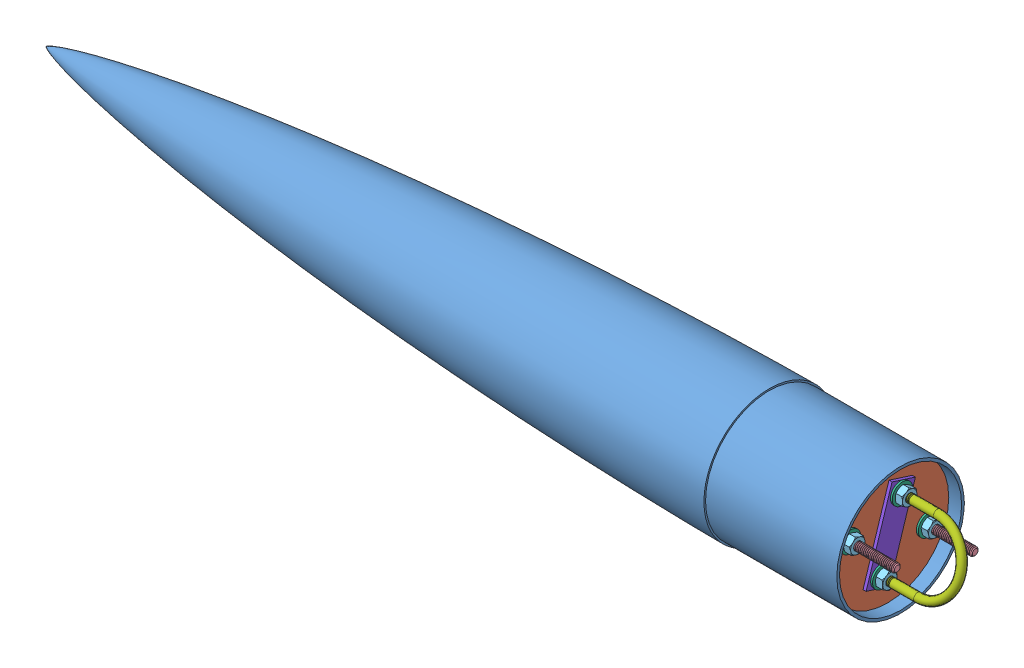
SolidWorks assembly NoseconeAssembly, configuration Default. Lengths in mm.
Overall size (713.54 119.45 119.45).
30 component instances, 8 part files, 72 mates.
Components (placement in the parent):
- NoseCone-1: NoseCone [Default] at (437.4105 322.4463 425.9996) size (664 101.6 101.6)
- CouplerBulkheadAft-1: CouplerBulkheadAft [Default] at (524.648 322.4463 425.9996) x (0 0.953259 -0.302155) z (0 -0.302155 -0.953259) size (95.15 4.76 95.15)
- CouplerBulkheadForward-1: CouplerBulkheadForward [Default] at (380.6605 322.4463 425.9996) x (0 -0.302155 -0.953259) z (0 0.953259 -0.302155) size (95.15 4.76 95.15)
- ThreadedRod_NC-1: ThreadedRod_NC [95475A576] at (465.494 312.8529 395.7337) x (1 0 0) z (0 -0.926581 -0.376095) size (206.33 6.43 7.33)
- ThreadedRod_NC-2: ThreadedRod_NC [95475A576] at (465.494 332.0398 456.2656) x (1 0 0) z (0 -0.612687 -0.790326) size (206.33 6.43 7.33)
- 91845A029_18-8 Stainless Steel Hex Nut-1: 91845A029_18-8 Stainless Steel Hex Nut [91845A029] at (371.6721 312.8529 395.7337) x (0 0.953259 -0.302155) z (-1 0 0) size (11.11 12.83 6.51)
- 91845A029_18-8 Stainless Steel Hex Nut-3: 91845A029_18-8 Stainless Steel Hex Nut [91845A029] at (371.6721 332.0398 456.2656) x (0 -0.953259 0.302155) z (-1 0 0) size (11.11 12.83 6.51)
- 91845A029_18-8 Stainless Steel Hex Nut-5: 91845A029_18-8 Stainless Steel Hex Nut [91845A029] at (384.8864 312.8529 395.7337) x (0 0.953259 -0.302155) z (-1 0 0) size (11.11 12.83 6.51)
- 91845A029_18-8 Stainless Steel Hex Nut-6: 91845A029_18-8 Stainless Steel Hex Nut [91845A029] at (384.8864 332.0398 456.2656) x (0 0.214956 -0.976624) z (1 0 0) size (11.11 12.83 6.51)
- 92141A029_18-8 Stainless Steel Washer-1: 92141A029_18-8 Stainless Steel Washer [92141A029] at (374.4502 312.8529 395.7337) x (0 -1 0) z (0 0 1) size (15.88 1.45 15.88)
- 92141A029_18-8 Stainless Steel Washer-3: 92141A029_18-8 Stainless Steel Washer [92141A029] at (380.6605 312.8529 395.7337) x (0 -1 0) z (0 0 1) size (15.88 1.45 15.88)
- 92141A029_18-8 Stainless Steel Washer-4: 92141A029_18-8 Stainless Steel Washer [92141A029] at (380.6605 332.0398 456.2656) x (0 0.711764 0.702418) z (0 0.702418 -0.711764) size (15.88 1.45 15.88)
- 92141A029_18-8 Stainless Steel Washer-5: 92141A029_18-8 Stainless Steel Washer [92141A029] at (374.4502 332.0398 456.2656) x (0 -0.99806 -0.062267) z (0 -0.062267 0.99806) size (15.88 1.45 15.88)
- 3043T618_U-Bolt-1: 3043T618_U-Bolt [3043T618] at (560.3742 322.4463 425.9996) x (0 -0.953259 0.302155) z (0 -0.302155 -0.953259) size (63.63 83.11 11.11)
- 8875T929_Mount Plate for 1 4 -20 Thread-1: 8875T929_Mount Plate for 1 4 -20 Thread [8875T929] at (529.4105 322.4463 425.9996) x (0 0.953259 -0.302155) z (1 0 0) size (66.67 19.05 2.38)
- 91845A029_18-8 Stainless Steel Hex Nut-7: 91845A029_18-8 Stainless Steel Hex Nut [91845A029] at (533.6364 332.0398 456.2656) x (0 0.214956 -0.976624) z (1 0 0) size (11.11 12.83 6.51)
- 91845A029_18-8 Stainless Steel Hex Nut-8: 91845A029_18-8 Stainless Steel Hex Nut [91845A029] at (520.4221 332.0398 456.2656) x (0 0.214956 -0.976624) z (1 0 0) size (11.11 12.83 6.51)
- 91845A029_18-8 Stainless Steel Hex Nut-9: 91845A029_18-8 Stainless Steel Hex Nut [91845A029] at (520.4221 312.8529 395.7337) x (0 0.953259 -0.302155) z (1 0 0) size (11.11 12.83 6.51)
- 91845A029_18-8 Stainless Steel Hex Nut-10: 91845A029_18-8 Stainless Steel Hex Nut [91845A029] at (533.6364 312.8529 395.7337) x (0 0.214956 -0.976624) z (1 0 0) size (11.11 12.83 6.51)
- 91845A029_18-8 Stainless Steel Hex Nut-11: 91845A029_18-8 Stainless Steel Hex Nut [91845A029] at (536.0177 298.2336 433.6744) x (0 0 1) z (1 0 0) size (11.11 12.83 6.51)
- 91845A029_18-8 Stainless Steel Hex Nut-12: 91845A029_18-8 Stainless Steel Hex Nut [91845A029] at (536.0177 346.6591 418.3249) x (0 0 1) z (1 0 0) size (11.11 12.83 6.51)
- 92141A029_18-8 Stainless Steel Washer-6: 92141A029_18-8 Stainless Steel Washer [92141A029] at (520.819 346.6591 418.3249) x (0 -0.381849 0.924225) z (0 0.924225 0.381849) size (15.88 1.45 15.88)
- 92141A029_18-8 Stainless Steel Washer-7: 92141A029_18-8 Stainless Steel Washer [92141A029] at (530.8583 332.0398 456.2656) x (0 0.996386 0.084943) z (0 -0.084943 0.996386) size (15.88 1.45 15.88)
- 92141A029_18-8 Stainless Steel Washer-8: 92141A029_18-8 Stainless Steel Washer [92141A029] at (524.648 332.0398 456.2656) x (0 0.994084 -0.108611) z (0 0.108611 0.994084) size (15.88 1.45 15.88)
- 92141A029_18-8 Stainless Steel Washer-9: 92141A029_18-8 Stainless Steel Washer [92141A029] at (530.8583 312.8529 395.7337) x (0 1 0) z (0 0 1) size (15.88 1.45 15.88)
- 92141A029_18-8 Stainless Steel Washer-10: 92141A029_18-8 Stainless Steel Washer [92141A029] at (531.7918 346.6591 418.3249) x (0 -0.381849 0.924225) z (0 0.924225 0.381849) size (15.88 1.45 15.88)
- 92141A029_18-8 Stainless Steel Washer-11: 92141A029_18-8 Stainless Steel Washer [92141A029] at (520.819 298.2336 433.6744) x (0 -0.381849 0.924225) z (0 0.924225 0.381849) size (15.88 1.45 15.88)
- 92141A029_18-8 Stainless Steel Washer-12: 92141A029_18-8 Stainless Steel Washer [92141A029] at (531.7918 298.2336 433.6744) x (0 -0.381849 0.924225) z (0 0.924225 0.381849) size (15.88 1.45 15.88)
- 92141A029_18-8 Stainless Steel Washer-13: 92141A029_18-8 Stainless Steel Washer [92141A029] at (524.648 312.8529 395.7337) x (0 1 0) z (0 0 1) size (15.88 1.45 15.88)
- 8875T929_Mount Plate for 1 4 -20 Thread-2: 8875T929_Mount Plate for 1 4 -20 Thread [8875T929] at (524.648 322.4463 425.9996) x (0 -0.953259 0.302155) z (-1 0 0) size (66.67 19.05 2.38)
Mates (geometry in assembly coordinates):
- Concentric1: concentric anti-aligned: cylinder of NoseCone-1 through (539.4105 322.4463 425.9996) axis (-1 0 0) radius 47.45; cylinder of CouplerBulkheadForward-1 through (375.898 322.4463 425.9996) axis (1 0 0) radius 47.575
- Concentric2: concentric aligned: cylinder of NoseCone-1 through (539.4105 322.4463 425.9996) axis (-1 0 0) radius 47.45; cylinder of CouplerBulkheadAft-1 through (529.4105 322.4463 425.9996) axis (-1 0 0) radius 47.575
- Distance1: distance = 158.75 mm aligned: plane of CouplerBulkheadForward-1 through (380.6605 322.4463 425.9996) normal (1 0 0); plane of NoseCone-1 through (539.4105 322.4463 425.9996) normal (1 0 0)
- Concentric3: concentric aligned: cylinder of CouplerBulkheadForward-1 through (380.6605 332.0398 456.2656) axis (-1 0 0) radius 3.175; circle of ThreadedRod_NC-2
- Concentric4: concentric aligned: cylinder of CouplerBulkheadForward-1 through (380.6605 312.8529 395.7337) axis (-1 0 0) radius 3.175; circle of ThreadedRod_NC-1
- Concentric5: concentric aligned: circle of ThreadedRod_NC-1; circle of 91845A029_18-8 Stainless Steel Hex Nut-1
- Concentric6: concentric anti-aligned: circle of ThreadedRod_NC-1; circle of 92141A029_18-8 Stainless Steel Washer-3
- Concentric7: concentric anti-aligned: circle of ThreadedRod_NC-1; circle of 92141A029_18-8 Stainless Steel Washer-1
- Concentric8: concentric aligned: circle of ThreadedRod_NC-1; circle of 91845A029_18-8 Stainless Steel Hex Nut-5
- Coincident3: coincident anti-aligned: plane of 91845A029_18-8 Stainless Steel Hex Nut-1 through (374.4502 306.5871 394.3545) normal (1 0 0); plane of 92141A029_18-8 Stainless Steel Washer-1 through (374.4502 312.8529 395.7337) normal (-1 0 0)
- Distance2: distance = 5 mm aligned: plane of ThreadedRod_NC-1 through (363.894 312.8529 395.7337) normal (-1 0 0); plane of 91845A029_18-8 Stainless Steel Hex Nut-1 through (368.894 306.5871 394.3545) normal (-1 0 0)
- Parallel1: parallel aligned: plane of 91845A029_18-8 Stainless Steel Hex Nut-1 through (368.894 317.1802 390.9969) normal (0 0.214956 -0.976624); plane of 91845A029_18-8 Stainless Steel Hex Nut-5 through (382.1083 317.1802 390.9969) normal (0 0.214956 -0.976624)
- Concentric9: concentric aligned: circle of ThreadedRod_NC-2; circle of 91845A029_18-8 Stainless Steel Hex Nut-3
- Concentric10: concentric anti-aligned: circle of ThreadedRod_NC-2; circle of 91845A029_18-8 Stainless Steel Hex Nut-6
- Concentric11: concentric anti-aligned: circle of ThreadedRod_NC-2; circle of 92141A029_18-8 Stainless Steel Washer-5
- Concentric12: concentric anti-aligned: circle of ThreadedRod_NC-2; circle of 92141A029_18-8 Stainless Steel Washer-4
- Coincident7: coincident anti-aligned: plane of 92141A029_18-8 Stainless Steel Washer-4 through (382.1083 332.0398 456.2656) normal (1 0 0); plane of 91845A029_18-8 Stainless Steel Hex Nut-6 through (382.1083 333.9783 462.3815) normal (-1 0 0)
- Coincident8: coincident aligned: plane of ThreadedRod_NC-1 through (363.894 312.8529 395.7337) normal (-1 0 0); plane of ThreadedRod_NC-2 through (363.894 332.0398 456.2656) normal (-1 0 0)
- Distance3: distance = 5 mm aligned: plane of 91845A029_18-8 Stainless Steel Hex Nut-3 through (368.894 338.3056 457.6447) normal (-1 0 0); plane of ThreadedRod_NC-2 through (363.894 332.0398 456.2656) normal (-1 0 0)
- Coincident10: coincident anti-aligned: plane of 91845A029_18-8 Stainless Steel Hex Nut-3 through (374.4502 338.3056 457.6447) normal (1 0 0); plane of 92141A029_18-8 Stainless Steel Washer-5 through (374.4502 332.0398 456.2656) normal (-1 0 0)
- Parallel2: parallel aligned: plane of 91845A029_18-8 Stainless Steel Hex Nut-3 through (368.894 336.367 451.5288) normal (0 0.214956 -0.976624); plane of 91845A029_18-8 Stainless Steel Hex Nut-6 through (387.6646 330.1012 450.1497) normal (0 0.214956 -0.976624)
- Coincident12: coincident aligned: plane of 91845A029_18-8 Stainless Steel Hex Nut-1 through (368.894 306.5871 394.3545) normal (0 -0.953259 0.302155); plane of 91845A029_18-8 Stainless Steel Hex Nut-3 through (368.894 325.7739 454.8865) normal (0 -0.953259 0.302155)
- Coincident14: coincident anti-aligned: plane of CouplerBulkheadForward-1 through (375.898 322.4463 425.9996) normal (-1 0 0); plane of 92141A029_18-8 Stainless Steel Washer-1 through (375.898 312.8529 395.7337) normal (1 0 0)
- Coincident15: coincident anti-aligned: plane of CouplerBulkheadForward-1 through (380.6605 322.4463 425.9996) normal (1 0 0); plane of 92141A029_18-8 Stainless Steel Washer-3 through (380.6605 312.8529 395.7337) normal (-1 0 0)
- Coincident16: coincident anti-aligned: plane of 91845A029_18-8 Stainless Steel Hex Nut-5 through (382.1083 306.5871 394.3545) normal (-1 0 0); plane of 92141A029_18-8 Stainless Steel Washer-3 through (382.1083 312.8529 395.7337) normal (1 0 0)
- Coincident17: coincident anti-aligned: plane of CouplerBulkheadForward-1 through (380.6605 322.4463 425.9996) normal (1 0 0); plane of 92141A029_18-8 Stainless Steel Washer-4 through (380.6605 332.0398 456.2656) normal (-1 0 0)
- Concentric13: concentric anti-aligned: cylinder of CouplerBulkheadAft-1 through (524.648 346.6591 418.3249) axis (1 0 0) radius 3.175; cylinder of 3043T618_U-Bolt-1 through (541.3242 346.6591 418.3249) axis (-1 0 0) radius 3.175
- Coincident18: coincident anti-aligned: circle of CouplerBulkheadAft-1; cylinder of 3043T618_U-Bolt-1 through (560.3742 298.2336 433.6744) axis (-1 0 0) radius 3.175
- Concentric14: concentric anti-aligned: cylinder of 3043T618_U-Bolt-1 through (541.3242 346.6591 418.3249) axis (-1 0 0) radius 3.175; cylinder of 92141A029_18-8 Stainless Steel Washer-10 through (531.7918 346.6591 418.3249) axis (1 0 0) radius 3.5687
- Concentric15: concentric anti-aligned: cylinder of 3043T618_U-Bolt-1 through (541.3242 346.6591 418.3249) axis (-1 0 0) radius 3.175; cylinder of 92141A029_18-8 Stainless Steel Washer-6 through (520.819 346.6591 418.3249) axis (1 0 0) radius 3.5687
- Concentric16: concentric anti-aligned: cylinder of 3043T618_U-Bolt-1 through (560.3742 298.2336 433.6744) axis (-1 0 0) radius 3.175; cylinder of 92141A029_18-8 Stainless Steel Washer-11 through (520.819 298.2336 433.6744) axis (1 0 0) radius 3.5687
- Concentric17: concentric anti-aligned: cylinder of 3043T618_U-Bolt-1 through (560.3742 298.2336 433.6744) axis (-1 0 0) radius 3.175; cylinder of 92141A029_18-8 Stainless Steel Washer-12 through (531.7918 298.2336 433.6744) axis (1 0 0) radius 3.5687
- Coincident19: coincident anti-aligned: cylinder of 3043T618_U-Bolt-1 through (541.3242 346.6591 418.3249) axis (-1 0 0) radius 3.175; circle of 91845A029_18-8 Stainless Steel Hex Nut-12
- Coincident20: coincident anti-aligned: cylinder of 3043T618_U-Bolt-1 through (560.3742 298.2336 433.6744) axis (-1 0 0) radius 3.175; circle of 91845A029_18-8 Stainless Steel Hex Nut-11
- Coincident21: coincident anti-aligned: plane of 3043T618_U-Bolt-1 through (520.819 341.9223 413.9976) normal (1 0 0); plane of 92141A029_18-8 Stainless Steel Washer-6 through (520.819 346.6591 418.3249) normal (-1 0 0)
- Coincident22: coincident anti-aligned: plane of 3043T618_U-Bolt-1 through (520.819 293.4968 429.3471) normal (1 0 0); plane of 92141A029_18-8 Stainless Steel Washer-11 through (520.819 298.2336 433.6744) normal (-1 0 0)
- Coincident23: coincident anti-aligned: plane of 91845A029_18-8 Stainless Steel Hex Nut-11 through (533.2396 295.0257 428.1181) normal (-1 0 0); plane of 92141A029_18-8 Stainless Steel Washer-12 through (533.2396 298.2336 433.6744) normal (1 0 0)
- Coincident24: coincident anti-aligned: plane of 91845A029_18-8 Stainless Steel Hex Nut-12 through (533.2396 343.4512 412.7687) normal (-1 0 0); plane of 92141A029_18-8 Stainless Steel Washer-10 through (533.2396 346.6591 418.3249) normal (1 0 0)
- Coincident25: coincident anti-aligned: cylinder of 3043T618_U-Bolt-1 through (541.3242 346.6591 418.3249) axis (-1 0 0) radius 3.175; circle of 8875T929_Mount Plate for 1 4 -20 Thread-1
- Coincident26: coincident anti-aligned: cylinder of 3043T618_U-Bolt-1 through (560.3742 298.2336 433.6744) axis (-1 0 0) radius 3.175; circle of 8875T929_Mount Plate for 1 4 -20 Thread-1
- Concentric18: concentric anti-aligned: cylinder of 3043T618_U-Bolt-1 through (541.3242 346.6591 418.3249) axis (-1 0 0) radius 3.175; cylinder of 8875T929_Mount Plate for 1 4 -20 Thread-2 through (522.2668 346.6591 418.3249) axis (1 0 0) radius 3.175
- Concentric19: concentric anti-aligned: cylinder of 3043T618_U-Bolt-1 through (560.3742 298.2336 433.6744) axis (-1 0 0) radius 3.175; cylinder of 8875T929_Mount Plate for 1 4 -20 Thread-2 through (522.2668 298.2336 433.6744) axis (1 0 0) radius 3.175
- Coincident27: coincident anti-aligned: plane of 92141A029_18-8 Stainless Steel Washer-6 through (522.2668 346.6591 418.3249) normal (1 0 0); plane of 8875T929_Mount Plate for 1 4 -20 Thread-2 through (522.2668 357.1036 425.0063) normal (-1 0 0)
- Coincident28: coincident anti-aligned: plane of CouplerBulkheadAft-1 through (524.648 322.4463 425.9996) normal (-1 0 0); plane of 8875T929_Mount Plate for 1 4 -20 Thread-2 through (524.648 357.1036 425.0063) normal (1 0 0)
- Coincident29: coincident anti-aligned: plane of CouplerBulkheadAft-1 through (529.4105 322.4463 425.9996) normal (1 0 0); plane of 8875T929_Mount Plate for 1 4 -20 Thread-1 through (529.4105 293.5451 445.1525) normal (-1 0 0)
- Coincident30: coincident anti-aligned: plane of 8875T929_Mount Plate for 1 4 -20 Thread-1 through (531.7918 293.5451 445.1525) normal (1 0 0); plane of 92141A029_18-8 Stainless Steel Washer-10 through (531.7918 346.6591 418.3249) normal (-1 0 0)
- Coincident31: coincident anti-aligned: plane of 8875T929_Mount Plate for 1 4 -20 Thread-1 through (531.7918 293.5451 445.1525) normal (1 0 0); plane of 92141A029_18-8 Stainless Steel Washer-12 through (531.7918 298.2336 433.6744) normal (-1 0 0)
- Concentric20: concentric aligned: cylinder of CouplerBulkheadAft-1 through (524.648 332.0398 456.2656) axis (1 0 0) radius 3.175; circle of ThreadedRod_NC-2
- Concentric21: concentric aligned: cylinder of CouplerBulkheadAft-1 through (524.648 312.8529 395.7337) axis (1 0 0) radius 3.175; circle of ThreadedRod_NC-1
- Distance4: distance = 10 mm aligned: plane of CouplerBulkheadAft-1 through (529.4105 322.4463 425.9996) normal (1 0 0); plane of NoseCone-1 through (539.4105 322.4463 425.9996) normal (1 0 0)
- Concentric22: concentric anti-aligned: circle of ThreadedRod_NC-1; cylinder of 92141A029_18-8 Stainless Steel Washer-13 through (524.648 312.8529 395.7337) axis (-1 0 0) radius 3.5687
- Concentric23: concentric anti-aligned: circle of ThreadedRod_NC-1; circle of 92141A029_18-8 Stainless Steel Washer-9
- Concentric24: concentric anti-aligned: circle of ThreadedRod_NC-2; circle of 92141A029_18-8 Stainless Steel Washer-7
- Concentric25: concentric anti-aligned: circle of ThreadedRod_NC-2; circle of 92141A029_18-8 Stainless Steel Washer-8
- Concentric26: concentric aligned: circle of ThreadedRod_NC-2; circle of 91845A029_18-8 Stainless Steel Hex Nut-8
- Concentric27: concentric aligned: circle of ThreadedRod_NC-2; circle of 91845A029_18-8 Stainless Steel Hex Nut-7
- Concentric28: concentric aligned: circle of ThreadedRod_NC-1; circle of 91845A029_18-8 Stainless Steel Hex Nut-9
- Concentric29: concentric aligned: circle of ThreadedRod_NC-1; circle of 91845A029_18-8 Stainless Steel Hex Nut-10
- Coincident33: coincident anti-aligned: plane of 91845A029_18-8 Stainless Steel Hex Nut-10 through (530.8583 314.7915 401.8496) normal (-1 0 0); plane of 92141A029_18-8 Stainless Steel Washer-9 through (530.8583 312.8529 395.7337) normal (1 0 0)
- Coincident34: coincident anti-aligned: plane of 91845A029_18-8 Stainless Steel Hex Nut-9 through (523.2002 308.5257 400.4705) normal (1 0 0); plane of 92141A029_18-8 Stainless Steel Washer-13 through (523.2002 312.8529 395.7337) normal (-1 0 0)
- Coincident35: coincident anti-aligned: plane of 91845A029_18-8 Stainless Steel Hex Nut-8 through (523.2002 333.9783 462.3815) normal (1 0 0); plane of 92141A029_18-8 Stainless Steel Washer-8 through (523.2002 332.0398 456.2656) normal (-1 0 0)
- Coincident37: coincident aligned: plane of 91845A029_18-8 Stainless Steel Hex Nut-9 through (523.2002 317.1802 390.9969) normal (0 0.953259 -0.302155); plane of 91845A029_18-8 Stainless Steel Hex Nut-10 through (536.4146 317.1802 390.9969) normal (0 0.953259 -0.302155)
- Coincident38: coincident aligned: plane of 91845A029_18-8 Stainless Steel Hex Nut-7 through (582.2158 336.367 451.5288) normal (0 0.953259 -0.302155); plane of 91845A029_18-8 Stainless Steel Hex Nut-10 through (536.4146 317.1802 390.9969) normal (0 0.953259 -0.302155)
- Coincident40: coincident aligned: plane of 91845A029_18-8 Stainless Steel Hex Nut-7 through (582.2158 336.367 451.5288) normal (0 0.953259 -0.302155); plane of 91845A029_18-8 Stainless Steel Hex Nut-8 through (523.2002 336.367 451.5288) normal (0 0.953259 -0.302155)
- Parallel4: parallel aligned: plane of 91845A029_18-8 Stainless Steel Hex Nut-6 through (387.6646 336.367 451.5288) normal (0 0.953259 -0.302155); plane of 91845A029_18-8 Stainless Steel Hex Nut-7 through (582.2158 336.367 451.5288) normal (0 0.953259 -0.302155)
- Coincident42: coincident anti-aligned: plane of 91845A029_18-8 Stainless Steel Hex Nut-7 through (530.8583 333.9783 462.3815) normal (-1 0 0); plane of 92141A029_18-8 Stainless Steel Washer-7 through (530.8583 332.0398 456.2656) normal (1 0 0)
- Parallel5: parallel aligned: plane of 91845A029_18-8 Stainless Steel Hex Nut-7 through (536.4146 336.367 451.5288) normal (0 0.953259 -0.302155); plane of 91845A029_18-8 Stainless Steel Hex Nut-8 through (523.2002 336.367 451.5288) normal (0 0.953259 -0.302155)
- Parallel6: parallel aligned: plane of 91845A029_18-8 Stainless Steel Hex Nut-7 through (536.4146 336.367 451.5288) normal (0 0.953259 -0.302155); plane of 91845A029_18-8 Stainless Steel Hex Nut-10 through (536.4146 317.1802 390.9969) normal (0 0.953259 -0.302155)
- Coincident45: coincident anti-aligned: plane of CouplerBulkheadAft-1 through (524.648 322.4463 425.9996) normal (-1 0 0); plane of 92141A029_18-8 Stainless Steel Washer-8 through (524.648 332.0398 456.2656) normal (1 0 0)
- Coincident46: coincident aligned: plane of CouplerBulkheadAft-1 through (524.648 322.4463 425.9996) normal (-1 0 0); circle of 92141A029_18-8 Stainless Steel Washer-13
- Coincident47: coincident anti-aligned: plane of CouplerBulkheadAft-1 through (529.4105 322.4463 425.9996) normal (1 0 0); circle of 92141A029_18-8 Stainless Steel Washer-9
- Coincident48: coincident anti-aligned: plane of CouplerBulkheadAft-1 through (529.4105 322.4463 425.9996) normal (1 0 0); plane of 92141A029_18-8 Stainless Steel Washer-7 through (529.4105 332.0398 456.2656) normal (-1 0 0)
